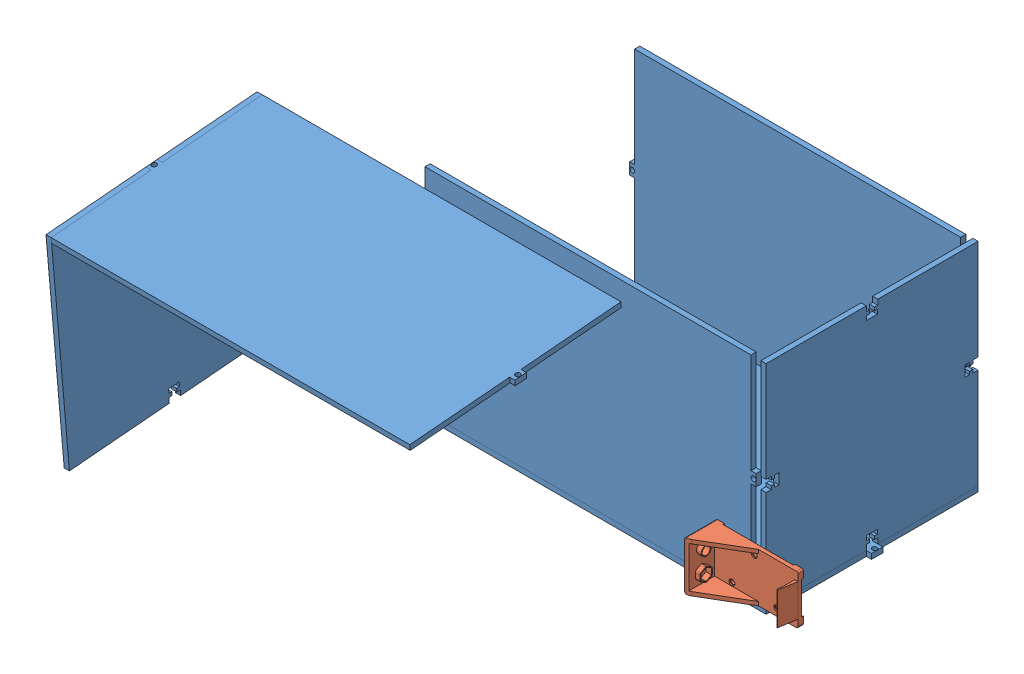
SolidWorks assembly Box1, configuration Default. Lengths in mm.
Overall size (452.66 172.22 278.05).
8 component instances, 3 part files, 11 mates.
Components (placement in the parent):
- Wall_Base-1: Wall_Base [Default] at (59.823 95.0811 167.655) size (226.36 3.18 130)
- Part1^Box1-1: Part1^Box1 [Default] at origin (virtual)
- Wall_Base-2: Wall_Base [wall_roof] at (-18.0547 219.0243 308.3158) x (1 0 0) z (0 -0.08596 0.996299) size (226.36 3.18 130)
- Wall_Base-3: Wall_Base [Wall_Aft] at (-131.2347 157.4331 303.0018) x (0 0.08596 -0.996299) z (0 -0.996299 -0.08596) size (130 3.18 130)
- Wall_Base-4: Wall_Base [Wall_Forward] at (169.823 163.2611 167.655) x (0 1 0) z (0 0 1) size (130 3.18 130)
- Wall_Base-5: Wall_Base [Wall_left] at (62.3869 163.2611 102.655) x (1 0 0) z (0 -1 0) size (206.36 3.18 130)
- Wall_Base-6: Wall_Base [Wall_Right] at (60.5398 163.2611 232.655) x (1 0 0) z (0 1 0) size (206.36 3.18 130)
- 9V Battery Holder-1: 9V Battery Holder [Default] at (294.674 244.3055 362.3886) size (53.5 30 19.31)
Mates (geometry in assembly coordinates):
- Coincident11: coincident anti-aligned: plane of Wall_Base-1 through (59.823 98.2611 167.655) normal (0 1 0); plane of Wall_Base-6 through (-39.4602 98.2611 229.475) normal (0 -1 0)
- Coincident12: coincident anti-aligned: line of Wall_Base-1 through (-50.177 98.2611 232.655) axis (1 0 0); line of Wall_Base-6 through (160.5398 98.2611 232.655) axis (-1 0 0)
- Coincident15: coincident anti-aligned: line of Wall_Base-1 through (-50.177 98.2611 232.655) axis (1 0 0); line of Wall_Base-3 through (-128.0547 98.2611 232.655) axis (-1 0 0)
- Coincident18: coincident anti-aligned: plane of Wall_Base-1 through (59.823 98.2611 167.655) normal (0 1 0); plane of Wall_Base-4 through (166.643 98.2611 102.655) normal (0 -1 0)
- Coincident19: coincident anti-aligned: line of Wall_Base-1 through (169.823 98.2611 232.655) axis (0 0 -1); line of Wall_Base-4 through (169.823 98.2611 102.655) axis (0 0 1)
- Coincident20: coincident aligned: plane of Wall_Base-1 through (-50.177 98.2611 232.655) normal (0 0 1); plane of Wall_Base-4 through (166.643 98.2611 232.655) normal (0 0 1)
- Coincident21: coincident anti-aligned: plane of Wall_Base-1 through (59.823 98.2611 167.655) normal (0 1 0); plane of Wall_Base-5 through (-37.6131 98.2611 105.835) normal (0 -1 0)
- Coincident22: coincident anti-aligned: line of Wall_Base-1 through (169.823 98.2611 102.655) axis (-1 0 0); line of Wall_Base-5 through (-37.6131 98.2611 102.655) axis (1 0 0)
- Coincident23: coincident anti-aligned: plane of Wall_Base-2 through (-131.2347 218.7234 311.8029) normal (0 -0.08596 0.996299); plane of Wall_Base-3 through (-131.2347 218.7234 311.8029) normal (0 0.08596 -0.996299)
- Coincident24: coincident anti-aligned: plane of Wall_Base-2 through (-18.0547 219.0243 308.3158) normal (0 -0.996299 -0.08596); plane of Wall_Base-3 through (-131.2347 219.0243 308.3158) normal (0 0.996299 0.08596)
- Coincident25: coincident aligned: plane of Wall_Base-2 through (-131.2347 219.0243 308.3158) normal (-1 0 0); plane of Wall_Base-3 through (-131.2347 157.4331 303.0018) normal (-1 0 0)
